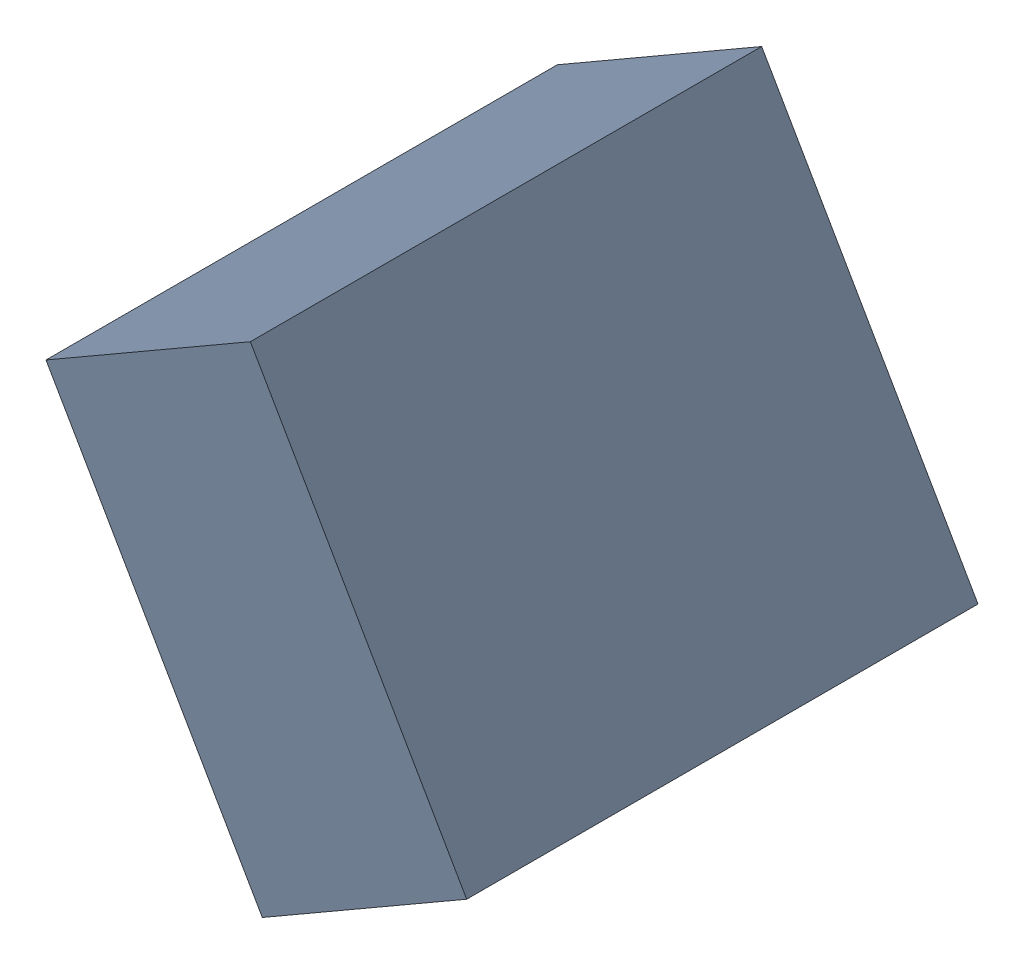
SolidWorks assembly C29_TDA5, configuration Standard. Lengths in mm.
Overall size (1.07 1.25 1.3).
2 component instances, 1 part files, 0 mates.
Components (placement in the parent):
- 885543192-1: 885543192 [Standard] at (-48.7472 -31.5432 0) size (1.07 1.25 1.3)
  - Extruded_27-1: Extruded_27 [Standard] at origin size (1.07 1.25 1.3)
